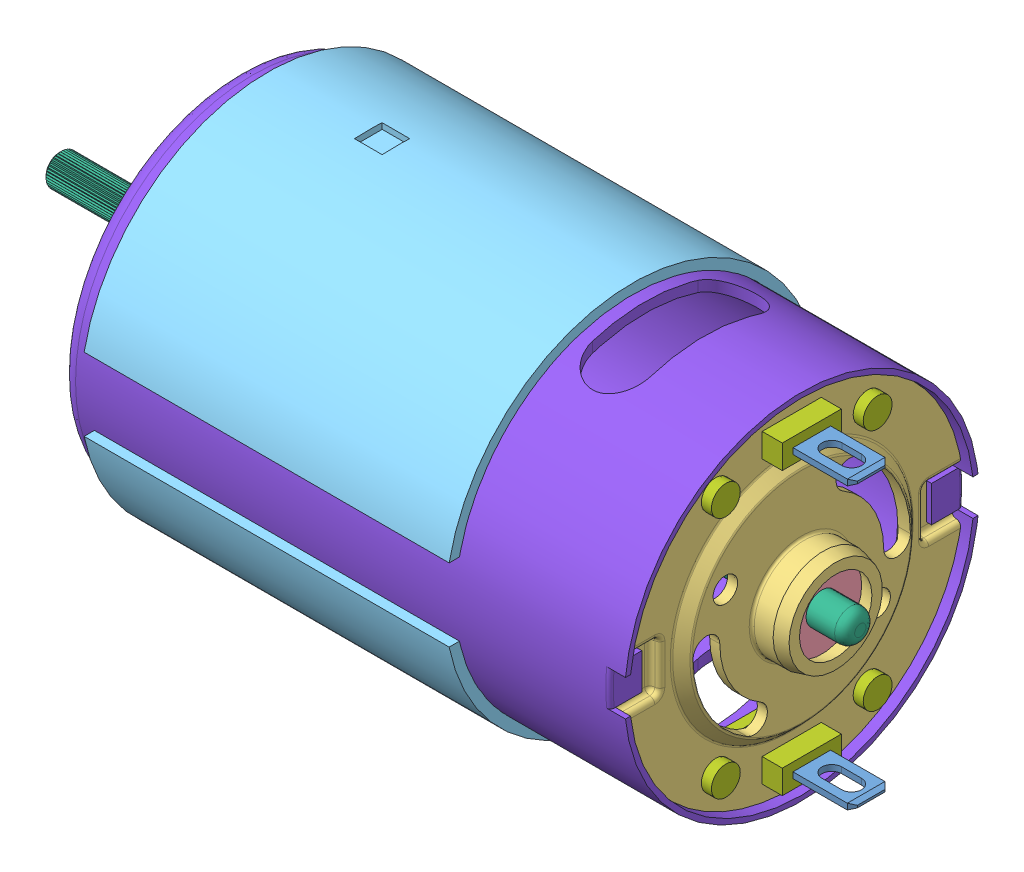
SolidWorks assembly am-0912 CCL-9015-Motor, configuration Default. Lengths in mm.
Overall size (82.02 37.83 37.47).
10 component instances, 8 part files, 0 mates.
Components (placement in the parent):
- AM-0912 terminal-1: AM-0912 terminal [Default] at (29.27 -13.055 -1.5854) size (10.06 0.6 3.8)
- AM-0912 output bushing-1: AM-0912 output bushing [Default] at (-28.166 1.123 -1.5904) size (4.5 10.97 10.97)
- AM-0912 end cap-1: AM-0912 end cap [Default] at (24.952 1.123 -1.5904) size (6.48 34.65 34.46)
- AM-0912 cap bushing-1: AM-0912 cap bushing [Default] at (31.302 1.123 -1.5904) size (3.04 8.08 8.08)
- AM-0912 shield-1: AM-0912 shield [Default] at (-21.634 1.123 -1.5904) x (1 0 0) z (0 -1 0) size (36.88 37.47 37.83)
- AM-0912 shaft-1: AM-0912 shaft [Default] at (-32.682 1.123 -1.5904) x (1 0 0) z (0 0.970706 0.240271) size (80.92 3.31 3.27)
- AM-0912 terminal housing-1: AM-0912 terminal housing [Default] at (30.286 -13.101 -1.5904) x (-1 0 0) z (0 0 1) size (4.06 4.83 19.05)
- AM-0912 terminal housing-2: AM-0912 terminal housing [Default] at (30.286 15.347 -1.5904) x (-1 0 0) z (0 0 -1) size (4.06 4.83 19.05)
- AM-0912 terminal-2: AM-0912 terminal [Default] at (29.27 15.301 -1.5954) size (10.06 0.6 3.8)
- AM-0912 housing-1: AM-0912 housing [Default] at (32.318 1.123 -1.5904) size (61.5 35.8 35.8)
